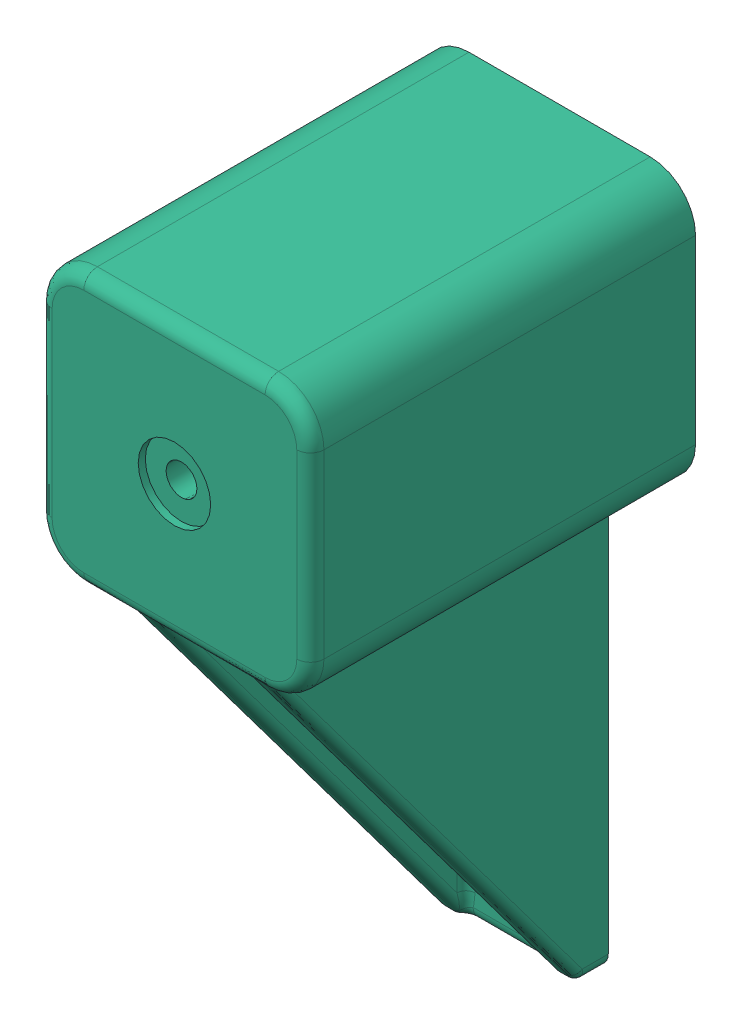
SolidWorks assembly Y Axis Belt Tensioner, configuration Default. Lengths in mm.
Overall size (60 160.17 95.71).
8 component instances, 6 part files, 15 mates.
Components (placement in the parent):
- 3764N125_High-Strength Gt Timing Belt Pulley-1: 3764N125_High-Strength Gt Timing Belt Pulley [3764N125] at (-41.6054 16.2086 -12.2741) x (0.760386 0 0.649471) z (0 -1 0) size (18.03 18.03 18)
- Tensioner Core-1: Tensioner Core [Default] at (-41.6054 16.2086 -24.2741) size (40 40 65)
- 6153K69_Stainless Steel Ball Bearing-1: 6153K69_Stainless Steel Ball Bearing [6153K69] at (-41.6054 29.7086 -12.2741) x (1 0 0) z (0 -1 0) size (16 16 5)
- 6153K69_Stainless Steel Ball Bearing-2: 6153K69_Stainless Steel Ball Bearing [6153K69] at (-41.6054 2.7086 -12.2741) x (1 0 0) z (0 1 0) size (16 16 5)
- 2mm spacer-1: 2mm spacer [Default] at (-41.6054 5.2086 -12.2741) size (9.5 2 9.5)
- 2mm spacer-2: 2mm spacer [Default] at (-41.6054 25.2086 -12.2741) size (9.5 2 9.5)
- Y Tensioner Shaft-1: Y Tensioner Shaft [Default] at (-41.6054 -2.7914 -12.2741) size (5 35 5)
- Y Tensioner Shell-1: Y Tensioner Shell [Default] at (-41.6054 16.2086 -14.2741) size (60 160.17 85)
Mates (geometry in assembly coordinates):
- Concentric1: concentric anti-aligned: cylinder of 3764N125_High-Strength Gt Timing Belt Pulley-1 through (-41.6054 7.2086 -12.2741) axis (0 -1 0) radius 2.5; cylinder of Tensioner Core-1 through (-41.6054 -3.7914 -12.2741) axis (0 1 0) radius 3.5
- Coincident1: coincident anti-aligned: plane of Tensioner Core-1 through (-41.6054 32.2086 -12.2741) normal (0 -1 0); plane of 6153K69_Stainless Steel Ball Bearing-1 through (-41.6054 32.2086 -9.5241) normal (0 1 0)
- Concentric2: concentric anti-aligned: cylinder of Tensioner Core-1 through (-41.6054 -3.7914 -12.2741) axis (0 1 0) radius 3.5; cylinder of 6153K69_Stainless Steel Ball Bearing-1 through (-41.6054 27.2086 -12.2741) axis (0 -1 0) radius 2.5
- Coincident2: coincident anti-aligned: plane of Tensioner Core-1 through (-41.6054 0.2086 -12.2741) normal (0 1 0); plane of 6153K69_Stainless Steel Ball Bearing-2 through (-41.6054 0.2086 -20.0241) normal (0 -1 0)
- Concentric3: concentric aligned: cylinder of Tensioner Core-1 through (-41.6054 -3.7914 -12.2741) axis (0 1 0) radius 3.5; cylinder of 6153K69_Stainless Steel Ball Bearing-2 through (-41.6054 5.2086 -12.2741) axis (0 1 0) radius 2.5
- Coincident3: coincident aligned: plane of 3764N125_High-Strength Gt Timing Belt Pulley-1 through (-35.7504 25.2086 -19.129) normal (0 1 0); circle of 2mm spacer-2
- Concentric4: concentric aligned: circle of 3764N125_High-Strength Gt Timing Belt Pulley-1; cylinder of 2mm spacer-2 through (-41.6054 27.2086 -12.2741) axis (0 -1 0) radius 2.6
- Coincident4: coincident anti-aligned: plane of 3764N125_High-Strength Gt Timing Belt Pulley-1 through (-39.9817 7.2086 -14.1751) normal (0 -1 0); plane of 2mm spacer-1 through (-41.6054 7.2086 -12.2741) normal (0 1 0)
- Concentric5: concentric anti-aligned: circle of 3764N125_High-Strength Gt Timing Belt Pulley-1; cylinder of 2mm spacer-1 through (-41.6054 7.2086 -12.2741) axis (0 -1 0) radius 2.6
- Concentric6: concentric anti-aligned: cylinder of Tensioner Core-1 through (-41.6054 -3.7914 -12.2741) axis (0 1 0) radius 3.5; cylinder of Y Tensioner Shaft-1 through (-41.6054 32.2086 -12.2741) axis (0 -1 0) radius 2.5
- Distance1: distance = 1 mm aligned: plane of Y Tensioner Shaft-1 through (-41.6054 -2.7914 -12.2741) normal (0 -1 0); plane of Tensioner Core-1 through (-61.6054 -3.7914 25.7259) normal (0 -1 0)
- Coincident6: coincident anti-aligned: plane of 6153K69_Stainless Steel Ball Bearing-1 through (-41.6054 27.2086 -7.5076) normal (0 -1 0); plane of 2mm spacer-2 through (-41.6054 27.2086 -12.2741) normal (0 1 0)
- Distance2: distance = 0.5 mm anti-aligned: plane of Tensioner Core-1 through (-61.6054 36.2086 25.7259) normal (0 1 0); plane of Y Tensioner Shell-1 through (-41.6054 36.7086 70.7259) normal (0 -1 0)
- Distance3: distance = 0.5 mm anti-aligned: plane of Tensioner Core-1 through (-21.6054 36.2086 25.7259) normal (1 0 0); plane of Y Tensioner Shell-1 through (-21.1054 16.2086 70.7259) normal (-1 0 0)
- Distance4: distance = 10 mm aligned: plane of Tensioner Core-1 through (-41.6054 16.2086 -24.2741) normal (0 0 -1); plane of Y Tensioner Shell-1 through (-61.6054 36.2086 -14.2741) normal (0 0 -1)
